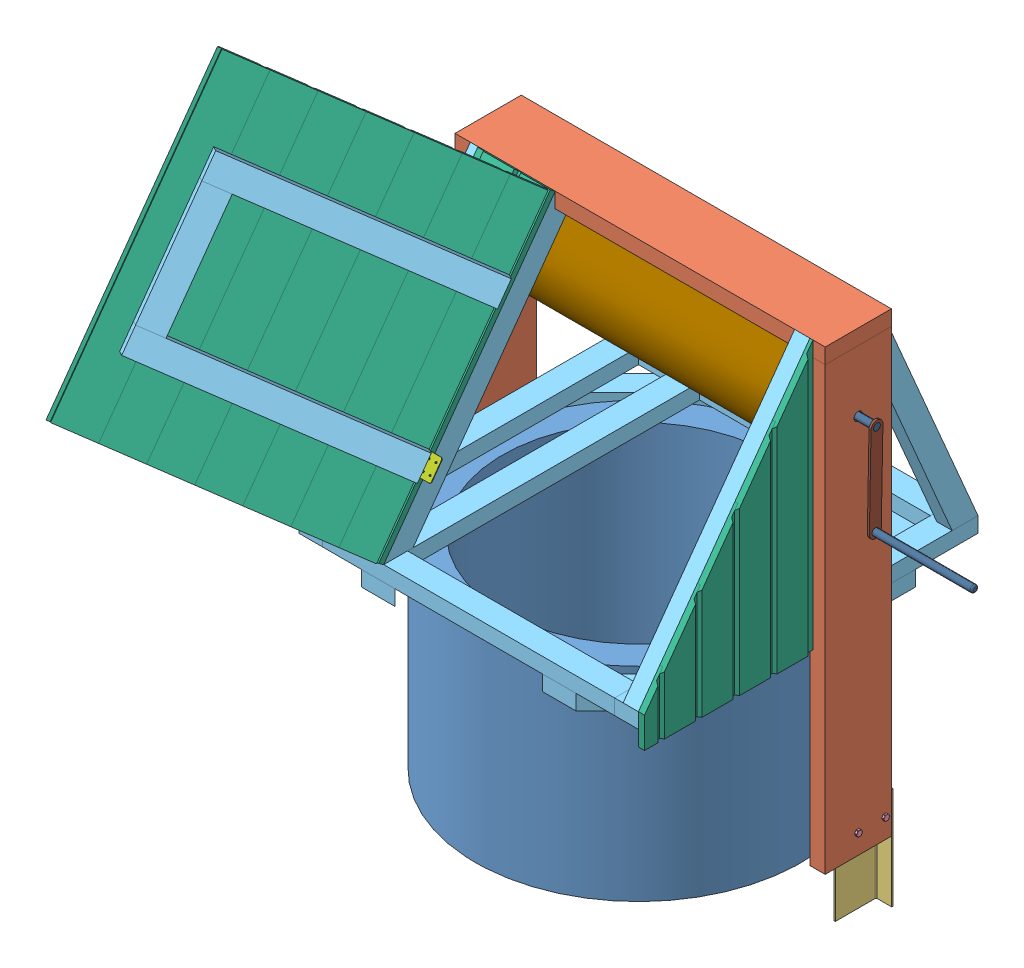
SolidWorks assembly well, configuration Default. Lengths in mm.
Overall size (1683.91 1861.34 1515.72).
55 component instances, 11 part files, 147 mates.
Components (placement in the parent):
- ring-1: ring [Default] at origin size (960 600 960)
- beam-45x195-1: beam-45x195 [Right] at (522.5 0 -102.5) x (0 0 -1) z (1 0 0) size (195 1300 45)
- beam-45x195-2: beam-45x195 [Left] at (-522.5 1300 -102.5) x (0 0 -1) z (-1 0 0) size (195 1300 45)
- beam-45x195-4: beam-45x195 [1090mm] at (545 1322.5 -102.5) x (0 0 1) z (0 -1 0) size (195 1090 45)
- side-mount-1: side-mount [Right] at (498 -180 -140) x (0 0 -1) z (1 0 0) size (124 300 50)
- side-mount-3: side-mount [Left] at (-498 120 -140) x (0 0 -1) z (-1 0 0) size (124 300 50)
- bolt-M10x60-1: bolt-M10x60 [Default] at (551.5 60 -180) x (0 1 0) z (0 0 1) size (16 66.5 17.98)
- bolt-M10x60-2: bolt-M10x60 [Default] at (551.5 60 -100) x (0 1 0) z (0 0 1) size (16 66.5 17.98)
- bolt-M10x60-4: bolt-M10x60 [Default] at (-551.5 60 -100) x (0 1 0) z (0 0 -1) size (16 66.5 17.98)
- bolt-M10x60-6: bolt-M10x60 [Default] at (-551.5 60 -180) x (0 1 0) z (0 0 -1) size (16 66.5 17.98)
- beam-45x70-1: beam-45x70 [1000mm] at (-465 622.5 -500) x (1 0 0) z (0 -1 0) size (70 1000 45)
- beam-45x70-2: beam-45x70 [1000mm] at (465 622.5 500) x (-1 0 0) z (0 -1 0) size (70 1000 45)
- beam-45x70-4: beam-45x70 [860mm] at (-430 622.5 465) x (0 0 1) z (0 1 0) size (70 860 45)
- beam-45x70-5: beam-45x70 [860mm] at (430 622.5 -465) x (0 0 -1) z (0 1 0) size (70 860 45)
- beam-45x70-7: beam-45x70 [860mm] at (-285 622.5 -430) x (1 0 0) z (0 -1 0) size (70 860 45)
- beam-45x70-8: beam-45x70 [Diagonal] at (-524.7487 577.5 241.906) x (-0.707107 0 0.707107) z (0 1 0) size (70 400 45)
- beam-45x70-9: beam-45x70 [Diagonal] at (524.7487 577.5 -241.906) x (0.707107 0 -0.707107) z (0 1 0) size (70 400 45)
- beam-45x70-11: beam-45x70 [Diagonal] at (241.906 577.5 524.7487) x (0.707107 0 0.707107) z (0 1 0) size (70 400 45)
- beam-45x70-13: beam-45x70 [Diagonal] at (-241.906 577.5 -524.7487) x (-0.707107 0 -0.707107) z (0 1 0) size (70 400 45)
- beam-45x70-15: beam-45x70 [Front diagonal] at (477.5 624.5226 471.6155) x (0 -0.585067 -0.810985) z (1 0 0) size (70 863.15 45)
- beam-45x70-17: beam-45x70 [Front diagonal] at (-477.5 624.5226 471.6155) x (0 -0.585067 -0.810985) z (1 0 0) size (70 863.15 45)
- beam-45x70-18: beam-45x70 [Front diagonal] at (-272.5 624.5226 471.6155) x (0 -0.585067 -0.810985) z (1 0 0) size (70 863.15 45)
- beam-45x70-20: beam-45x70 [Rear diagonal] at (-477.5 631.2128 -467.8299) x (0 -0.393919 0.919145) z (-1 0 0) size (70 761.58 45)
- beam-45x70-22: beam-45x70 [Rear diagonal] at (477.5 631.2128 -467.8299) x (0 -0.393919 0.919145) z (-1 0 0) size (70 761.58 45)
- weatherboard-18x120-1: weatherboard-18x120 [Right A] at (509 555 55) x (0 0 1) z (-1 0 0) size (120 790 18)
- weatherboard-18x120-3: weatherboard-18x120 [Right B] at (509 555 165.5) x (0 0 1) z (-1 0 0) size (120 636.83 18)
- weatherboard-18x120-6: weatherboard-18x120 [Right C] at (509 555 276) x (0 0 1) z (-1 0 0) size (120 483.66 18)
- weatherboard-18x120-8: weatherboard-18x120 [Right D] at (509 555 386.5) x (0 0 1) z (-1 0 0) size (120 330.5 18)
- weatherboard-18x120-10: weatherboard-18x120 [Right E] at (509 555 497) x (0 0 1) z (-1 0 0) size (63 177.33 18)
- weatherboard-18x120-12: weatherboard-18x120 [Front diagonal door mount] at (-300.5 1350.2656 2.2989) x (1 0 0) z (0 -0.585067 -0.810985) size (110.5 863.15 18)
- weatherboard-18x120-13: weatherboard-18x120 [Front diagonal normal] at (-411 1350.2656 2.2989) x (1 0 0) z (0 -0.585067 -0.810985) size (120 863.15 18)
- hinge-1: hinge [Default] at (-250 1170.76 146.5962) x (0 0.585067 0.810985) z (0 -0.810985 0.585067) size (70.41 34.65 60) (flexible)
  - hinge-side-1: hinge-side [A] at origin size (43 6 60)
  - hinge-side-2: hinge-side [B] at (2.1213 0.8787 0) x (-0.707107 -0.707107 0) z (0 0 -1) size (43 6 60)
  - hinge-pin-1: hinge-pin [Default] at (0 3 -30) x (1 0 0) z (0 -1 0) size (1.9 60 1.9)
- hinge-2: hinge [Default] at (-253 842.0577 380.0322) x (-1 0 0) z (0 0.810985 -0.585067) size (43 43 60) (flexible)
  - hinge-side-1: hinge-side [A] at origin size (43 6 60)
  - hinge-side-2: hinge-side [B] at (-3 3 0) x (0 1 0) z (0 0 -1) size (43 6 60)
  - hinge-pin-1: hinge-pin [Default] at (0 3 -30) x (0.057006 -0.998374 0) z (-0.998374 -0.057006 0) size (1.9 60 1.9)
- weatherboard-18x120-14: weatherboard-18x120 [Front diagonal door first] at (-272.3067 1378.5111 41.451) x (-0.707107 0.413705 0.573453) z (0.707107 0.413705 0.573453) size (96.3 863.15 18)
- beam-45x70-23: beam-45x70 [680mm] at (-705.1948 1471.3168 563.2096) x (0 0.810985 -0.585067) z (-0.707107 -0.413705 -0.573453) size (70 680 45)
- beam-45x70-24: beam-45x70 [680mm] at (-705.1948 1144.3697 799.0786) x (0 0.810985 -0.585067) z (-0.707107 -0.413705 -0.573453) size (70 680 45)
- beam-45x70-26: beam-45x70 [Door handle brace] at (-680.446 617.468 1148.6836) x (-0.707107 0.413705 0.573453) z (-0.707107 -0.413705 -0.573453) size (70 333.15 45)
- weatherboard-18x120-15: weatherboard-18x120 [Front diagonal normal] at (-350.442 1424.2255 104.8175) x (-0.707107 0.413705 0.573453) z (0.707107 0.413705 0.573453) size (120 863.15 18)
- weatherboard-18x120-16: weatherboard-18x120 [Front diagonal normal] at (-428.5773 1469.9399 168.1841) x (-0.707107 0.413705 0.573453) z (0.707107 0.413705 0.573453) size (120 863.15 18)
- weatherboard-18x120-17: weatherboard-18x120 [Front diagonal normal] at (-506.7126 1515.6544 231.5506) x (-0.707107 0.413705 0.573453) z (0.707107 0.413705 0.573453) size (120 863.15 18)
- weatherboard-18x120-18: weatherboard-18x120 [Front diagonal normal] at (-584.8479 1561.3688 294.9171) x (-0.707107 0.413705 0.573453) z (0.707107 0.413705 0.573453) size (120 863.15 18)
- weatherboard-18x120-19: weatherboard-18x120 [Front diagonal normal] at (-662.9832 1607.0832 358.2836) x (-0.707107 0.413705 0.573453) z (0.707107 0.413705 0.573453) size (120 863.15 18)
- weatherboard-18x120-20: weatherboard-18x120 [Front diagonal normal] at (-741.1185 1652.7976 421.6502) x (-0.707107 0.413705 0.573453) z (0.707107 0.413705 0.573453) size (120 863.15 18)
- roll-1: roll [Default] at (-450 1120 -102.5) x (0 -0.018379 -0.999831) z (1 0 0) size (250 250 900)
- bar-1: bar [Chamfered] at (-50 1120 -102.5) x (0 0.181671 0.983359) z (-1 0 0) size (20 20 500)
- handle-1: handle [Default] at (594 987.5224 -100.0648) x (0 -0.018379 -0.999831) z (0 -0.999831 0.018379) size (35 794 300)
  - handle-link-1: handle-link [Default] at origin size (35 6 300)
  - bar-1: bar [300mm] at (0 0 132.5) x (0.999562 0 -0.029607) z (0 1 0) size (20 20 300)
  - bar-2: bar [Chamfered] at (0 -494 -132.5) x (-0.665343 0 0.746538) z (0 1 0) size (20 20 500)
Mates (geometry in assembly coordinates):
- Coincident1: coincident aligned: plane of side-mount-1 through (498 120 -200) normal (0 0 1); plane of assembly through (0 0 -200) normal (0 0 1)
- Distance1: distance = 120 mm anti-aligned: plane of side-mount-1 through (498 120 -140) normal (0 1 0); plane of ring-1 through (0 0 0) normal (0 -1 0)
- Distance2: distance = 500 mm aligned: plane of side-mount-1 through (500 120 -140) normal (1 0 0); plane of assembly through (0 0 0) normal (1 0 0)
- Concentric1: concentric anti-aligned: cylinder of side-mount-1 through (495.999 60 -180) axis (1 0 0) radius 5.25; cylinder of ? through (-680.6384 60 -180) axis (-1 0 0) radius 5.25
- Concentric2: concentric anti-aligned: cylinder of side-mount-1 through (495.999 60 -100) axis (1 0 0) radius 5.25; cylinder of ? through (-680.6384 60 -100) axis (-1 0 0) radius 5.25
- Symmetric2: symmetric aligned: plane of side-mount-1 through (496 120 -140) normal (-1 0 0); plane of ? through (-496 120 -140) normal (1 0 0); plane of assembly through (0 0 0) normal (1 0 0)
- Concentric3: concentric anti-aligned: cylinder of side-mount-1 through (495.999 60 -180) axis (1 0 0) radius 5.25; cylinder of side-mount-3 through (-495.999 60 -180) axis (-1 0 0) radius 5.25
- Concentric4: concentric anti-aligned: cylinder of side-mount-1 through (495.999 60 -100) axis (1 0 0) radius 5.25; cylinder of side-mount-3 through (-495.999 60 -100) axis (-1 0 0) radius 5.25
- Coincident6: coincident aligned: plane of side-mount-1 through (498 120 -200) normal (0 0 1); plane of side-mount-3 through (-498 -180 -200) normal (0 0 1)
- Coincident7: coincident aligned: plane of side-mount-1 through (498 120 -140) normal (0 1 0); plane of side-mount-3 through (-498 120 -140) normal (0 1 0)
- Symmetric3: symmetric aligned: plane of side-mount-1 through (496 120 -140) normal (-1 0 0); plane of side-mount-3 through (-496 -180 -140) normal (1 0 0); plane of assembly through (0 0 0) normal (1 0 0)
- Coincident8: coincident anti-aligned: plane of side-mount-1 through (500 120 -140) normal (1 0 0); plane of beam-45x195-1 through (500 1300 -5) normal (-1 0 0)
- Coincident9: coincident anti-aligned: plane of side-mount-1 through (498 120 -200) normal (0 0 1); plane of beam-45x195-1 through (500 1300 -200) normal (0 0 -1)
- Coincident10: coincident aligned: plane of ring-1 through (0 0 0) normal (0 -1 0); plane of beam-45x195-1 through (522.5 0 -102.5) normal (0 -1 0)
- Coincident11: coincident anti-aligned: plane of beam-45x195-1 through (545 1300 -5) normal (1 0 0); plane of bolt-M10x60-1 through (545 60 -180) normal (-1 0 0)
- Concentric5: concentric aligned: cylinder of side-mount-1 through (495.999 60 -180) axis (1 0 0) radius 5.25; cylinder of bolt-M10x60-1 through (485 60 -180) axis (1 0 0) radius 5
- Coincident12: coincident anti-aligned: plane of beam-45x195-1 through (545 1300 -5) normal (1 0 0); plane of bolt-M10x60-2 through (545 60 -100) normal (-1 0 0)
- Concentric6: concentric aligned: cylinder of side-mount-1 through (495.999 60 -100) axis (1 0 0) radius 5.25; cylinder of bolt-M10x60-2 through (485 60 -100) axis (1 0 0) radius 5
- Coincident14: coincident anti-aligned: plane of side-mount-3 through (-500 -180 -140) normal (-1 0 0); plane of beam-45x195-2 through (-500 0 -5) normal (1 0 0)
- Coincident15: coincident anti-aligned: plane of side-mount-3 through (-498 -180 -200) normal (0 0 1); plane of beam-45x195-2 through (-500 0 -200) normal (0 0 -1)
- Coincident18: coincident aligned: plane of ring-1 through (0 0 0) normal (0 -1 0); plane of beam-45x195-2 through (-522.5 0 -102.5) normal (0 -1 0)
- Parallel1: parallel aligned: plane of beam-45x195-1 through (522.5 0 -102.5) normal (0 -1 0); plane of bolt-M10x60-2 through (545 52 -104.6188) normal (0 -1 0)
- Parallel2: parallel aligned: plane of beam-45x195-1 through (522.5 0 -102.5) normal (0 -1 0); plane of bolt-M10x60-1 through (545 52 -184.6188) normal (0 -1 0)
- Coincident21: coincident anti-aligned: plane of beam-45x195-2 through (-545 0 -5) normal (-1 0 0); plane of bolt-M10x60-4 through (-545 60 -100) normal (1 0 0)
- Concentric7: concentric aligned: cylinder of side-mount-3 through (-495.999 60 -100) axis (-1 0 0) radius 5.25; cylinder of bolt-M10x60-4 through (-485 60 -100) axis (-1 0 0) radius 5
- Parallel3: parallel aligned: plane of beam-45x195-2 through (-522.5 0 -102.5) normal (0 -1 0); plane of bolt-M10x60-4 through (-545 52 -95.3812) normal (0 -1 0)
- Coincident22: coincident anti-aligned: plane of beam-45x195-2 through (-545 0 -5) normal (-1 0 0); plane of bolt-M10x60-6 through (-545 60 -180) normal (1 0 0)
- Concentric8: concentric aligned: cylinder of side-mount-3 through (-495.999 60 -180) axis (-1 0 0) radius 5.25; cylinder of bolt-M10x60-6 through (-485 60 -180) axis (-1 0 0) radius 5
- Parallel4: parallel aligned: plane of beam-45x195-2 through (-522.5 0 -102.5) normal (0 -1 0); plane of bolt-M10x60-6 through (-545 52 -175.3812) normal (0 -1 0)
- Coincident23: coincident anti-aligned: plane of beam-45x195-2 through (-522.5 1300 -102.5) normal (0 1 0); plane of beam-45x195-4 through (-545 1300 -200) normal (0 -1 0)
- Coincident24: coincident aligned: plane of beam-45x195-2 through (-545 0 -5) normal (-1 0 0); plane of beam-45x195-4 through (-545 1322.5 -102.5) normal (-1 0 0)
- Coincident25: coincident aligned: plane of beam-45x195-2 through (-500 0 -5) normal (0 0 1); plane of beam-45x195-4 through (-545 1345 -5) normal (0 0 1)
- Coincident26: coincident anti-aligned: plane of ring-1 through (0 600 0) normal (0 1 0); plane of beam-45x70-1 through (-500 600 500) normal (0 -1 0)
- Coincident27: coincident anti-aligned: plane of beam-45x195-2 through (-500 0 -5) normal (1 0 0); plane of beam-45x70-1 through (-500 645 500) normal (-1 0 0)
- Symmetric4: symmetric aligned: plane of beam-45x70-1 through (-465 622.5 500) normal (0 0 1); plane of beam-45x70-1 through (-465 622.5 -500) normal (0 0 -1); plane of assembly through (0 0 0) normal (0 0 1)
- Coincident28: coincident anti-aligned: plane of ring-1 through (0 600 0) normal (0 1 0); plane of beam-45x70-2 through (500 600 -500) normal (0 -1 0)
- Coincident29: coincident anti-aligned: plane of beam-45x195-1 through (500 1300 -5) normal (-1 0 0); plane of beam-45x70-2 through (500 645 -500) normal (1 0 0)
- Symmetric5: symmetric aligned: plane of beam-45x70-2 through (465 622.5 -500) normal (0 0 -1); plane of beam-45x70-2 through (465 622.5 500) normal (0 0 1); plane of assembly through (0 0 0) normal (0 0 1)
- Coincident31: coincident aligned: plane of beam-45x70-1 through (-500 645 500) normal (0 1 0); plane of beam-45x70-4 through (430 645 430) normal (0 1 0)
- Coincident32: coincident anti-aligned: plane of beam-45x70-1 through (-430 645 500) normal (1 0 0); plane of beam-45x70-4 through (-430 622.5 465) normal (-1 0 0)
- Coincident33: coincident aligned: plane of beam-45x70-1 through (-465 622.5 500) normal (0 0 1); plane of beam-45x70-4 through (430 600 500) normal (0 0 1)
- Coincident34: coincident aligned: plane of beam-45x70-1 through (-500 645 500) normal (0 1 0); plane of beam-45x70-5 through (-430 645 -430) normal (0 1 0)
- Coincident35: coincident anti-aligned: plane of beam-45x70-2 through (430 645 -500) normal (-1 0 0); plane of beam-45x70-5 through (430 622.5 -465) normal (1 0 0)
- Coincident36: coincident aligned: plane of beam-45x70-2 through (465 622.5 -500) normal (0 0 -1); plane of beam-45x70-5 through (-430 600 -500) normal (0 0 -1)
- Coincident38: coincident aligned: plane of beam-45x70-1 through (-500 645 500) normal (0 1 0); plane of beam-45x70-7 through (-320 645 430) normal (0 1 0)
- Coincident39: coincident anti-aligned: plane of beam-45x70-4 through (430 600 430) normal (0 0 -1); plane of beam-45x70-7 through (-285 622.5 430) normal (0 0 1)
- Distance3: distance = 250 mm anti-aligned: plane of beam-45x70-7 through (-250 645 430) normal (1 0 0); plane of beam-45x70-1 through (-500 645 500) normal (-1 0 0)
- Coincident45: coincident aligned: plane of beam-45x70-4 through (430 600 500) normal (0 0 1); plane of beam-45x70-8 through (-524.7487 554.999 500) normal (0 0 1)
- Coincident46: coincident aligned: plane of beam-45x70-1 through (-500 645 500) normal (-1 0 0); plane of beam-45x70-8 through (-500 554.999 241.906) normal (-1 0 0)
- Coincident47: coincident anti-aligned: plane of beam-45x70-1 through (-500 600 500) normal (0 -1 0); plane of beam-45x70-8 through (-217.1573 600 500) normal (0 1 0)
- Coincident48: coincident aligned: plane of beam-45x70-5 through (-430 600 -500) normal (0 0 -1); plane of beam-45x70-9 through (524.7487 554.999 -500) normal (0 0 -1)
- Coincident49: coincident aligned: plane of beam-45x70-2 through (500 645 -500) normal (1 0 0); plane of beam-45x70-9 through (500 554.999 -241.906) normal (1 0 0)
- Coincident50: coincident anti-aligned: plane of beam-45x70-2 through (500 600 -500) normal (0 -1 0); plane of beam-45x70-9 through (217.1573 600 -500) normal (0 1 0)
- Coincident51: coincident aligned: plane of beam-45x70-2 through (500 645 -500) normal (1 0 0); plane of beam-45x70-11 through (500 554.999 524.7487) normal (1 0 0)
- Coincident52: coincident aligned: plane of beam-45x70-2 through (465 622.5 500) normal (0 0 1); plane of beam-45x70-11 through (241.906 554.999 500) normal (0 0 1)
- Coincident53: coincident anti-aligned: plane of beam-45x70-2 through (500 600 -500) normal (0 -1 0); plane of beam-45x70-11 through (500 600 217.1573) normal (0 1 0)
- Coincident54: coincident aligned: plane of beam-45x70-1 through (-500 645 500) normal (-1 0 0); plane of beam-45x70-13 through (-500 554.999 -524.7487) normal (-1 0 0)
- Coincident55: coincident aligned: plane of beam-45x70-1 through (-465 622.5 -500) normal (0 0 -1); plane of beam-45x70-13 through (-241.906 554.999 -500) normal (0 0 -1)
- Coincident56: coincident anti-aligned: plane of beam-45x70-1 through (-500 600 500) normal (0 -1 0); plane of beam-45x70-13 through (-500 600 -217.1573) normal (0 1 0)
- Coincident57: coincident aligned: line of beam-45x70-2 through (430 645 500) axis (1 0 0); line of beam-45x70-15 through (455 645 500) axis (1 0 0)
- Coincident58: coincident: line of beam-45x195-4 through (-545 1345 -5) axis (1 0 0); plane of beam-45x70-15 through (455 1455.9846 -85.0675) normal (0 0.585067 0.810985)
- Coincident59: coincident aligned: plane of beam-45x70-2 through (500 645 -500) normal (1 0 0); plane of beam-45x70-15 through (500 1455.9846 -85.0675) normal (1 0 0)
- Coincident63: coincident anti-aligned: line of beam-45x70-1 through (-430 645 500) axis (-1 0 0); line of beam-45x70-17 through (-500 645 500) axis (1 0 0)
- Coincident64: coincident aligned: line of beam-45x195-4 through (-545 1345 -5) axis (1 0 0); line of beam-45x70-17 through (-500 1345 -5) axis (1 0 0)
- Coincident65: coincident aligned: plane of beam-45x70-1 through (-500 645 500) normal (-1 0 0); plane of beam-45x70-17 through (-500 1455.9846 -85.0675) normal (-1 0 0)
- Coincident66: coincident anti-aligned: line of beam-45x70-1 through (-430 645 500) axis (-1 0 0); line of beam-45x70-18 through (-295 645 500) axis (1 0 0)
- Coincident67: coincident aligned: line of beam-45x195-4 through (-545 1345 -5) axis (1 0 0); line of beam-45x70-18 through (-295 1345 -5) axis (1 0 0)
- Coincident71: coincident aligned: plane of beam-45x70-7 through (-250 645 430) normal (1 0 0); plane of beam-45x70-18 through (-250 1455.9846 -85.0675) normal (1 0 0)
- Coincident73: coincident: line of beam-45x195-4 through (-545 1345 -200) axis (1 0 0); plane of beam-45x70-20 through (-455 1564.145 -106.0807) normal (0 0.393919 -0.919145)
- Coincident74: coincident aligned: plane of beam-45x70-1 through (-500 645 500) normal (-1 0 0); plane of beam-45x70-20 through (-500 1564.145 -106.0807) normal (-1 0 0)
- Coincident75: coincident aligned: line of beam-45x70-1 through (-430 645 -500) axis (-1 0 0); line of beam-45x70-20 through (-455 645 -500) axis (-1 0 0)
- Coincident79: coincident anti-aligned: line of beam-45x70-2 through (430 645 -500) axis (1 0 0); line of beam-45x70-22 through (500 645 -500) axis (-1 0 0)
- Coincident80: coincident anti-aligned: line of beam-45x195-4 through (-545 1345 -200) axis (1 0 0); line of beam-45x70-22 through (500 1345 -200) axis (-1 0 0)
- Coincident81: coincident aligned: plane of beam-45x70-2 through (500 645 -500) normal (1 0 0); plane of beam-45x70-22 through (500 1564.145 -106.0807) normal (1 0 0)
- Coincident82: coincident anti-aligned: plane of beam-45x70-2 through (500 645 -500) normal (1 0 0); plane of weatherboard-18x120-1 through (500 1355 55) normal (-1 0 0)
- Coincident83: coincident anti-aligned: plane of beam-45x195-1 through (500 1300 -5) normal (0 0 1); plane of weatherboard-18x120-1 through (509 1355 -5) normal (0 0 -1)
- Distance4: distance = 45 mm aligned: plane of weatherboard-18x120-1 through (509 555 55) normal (0 -1 0); plane of beam-45x70-2 through (500 600 -500) normal (0 -1 0)
- Coincident88: coincident anti-aligned: plane of weatherboard-18x120-1 through (509 1355 105.5) normal (0 0 1); plane of weatherboard-18x120-3 through (509 1355 105.5) normal (0 0 -1)
- Coincident89: coincident aligned: plane of weatherboard-18x120-1 through (509 555 55) normal (0 -1 0); plane of weatherboard-18x120-3 through (509 555 165.5) normal (0 -1 0)
- Coincident90: coincident anti-aligned: plane of weatherboard-18x120-1 through (509 1355 55) normal (-1 0 0); plane of weatherboard-18x120-3 through (509 1355 165.5) normal (1 0 0)
- Coincident91: coincident anti-aligned: plane of weatherboard-18x120-3 through (509 1500 216) normal (0 0 1); plane of ? through (362.1952 1500 216) normal (0 0 -1)
- Coincident92: coincident aligned: plane of weatherboard-18x120-1 through (509 500 55) normal (0 -1 0); plane of ? through (362.1952 500 276) normal (0 -1 0)
- Coincident94: coincident anti-aligned: plane of weatherboard-18x120-3 through (509 1500 165.5) normal (-1 0 0); plane of ? through (509 1500 276) normal (1 0 0)
- Coincident95: coincident anti-aligned: plane of weatherboard-18x120-3 through (509 1355 216) normal (0 0 1); plane of weatherboard-18x120-6 through (509 1355 216) normal (0 0 -1)
- Coincident96: coincident aligned: plane of weatherboard-18x120-3 through (509 555 165.5) normal (0 -1 0); plane of weatherboard-18x120-6 through (509 555 276) normal (0 -1 0)
- Coincident98: coincident anti-aligned: plane of weatherboard-18x120-3 through (509 1355 165.5) normal (-1 0 0); plane of weatherboard-18x120-6 through (509 1355 276) normal (1 0 0)
- Coincident99: coincident anti-aligned: plane of weatherboard-18x120-6 through (509 1355 326.5) normal (0 0 1); plane of weatherboard-18x120-8 through (509 1355 326.5) normal (0 0 -1)
- Coincident100: coincident aligned: plane of weatherboard-18x120-6 through (509 555 276) normal (0 -1 0); plane of weatherboard-18x120-8 through (509 555 386.5) normal (0 -1 0)
- Coincident101: coincident anti-aligned: plane of weatherboard-18x120-6 through (509 1355 276) normal (-1 0 0); plane of weatherboard-18x120-8 through (509 1355 386.5) normal (1 0 0)
- Coincident102: coincident anti-aligned: plane of weatherboard-18x120-8 through (509 1355 437) normal (0 0 1); plane of weatherboard-18x120-10 through (509 1355 437) normal (0 0 -1)
- Coincident103: coincident aligned: plane of weatherboard-18x120-8 through (509 555 386.5) normal (0 -1 0); plane of weatherboard-18x120-10 through (509 555 497) normal (0 -1 0)
- Coincident104: coincident anti-aligned: plane of weatherboard-18x120-8 through (509 1355 386.5) normal (-1 0 0); plane of weatherboard-18x120-10 through (509 1355 497) normal (1 0 0)
- Coincident105: coincident anti-aligned: plane of beam-45x70-17 through (-500 1455.9846 -85.0675) normal (0 0.585067 0.810985); plane of weatherboard-18x120-12 through (-300.5 534.0154 580.0675) normal (0 -0.585067 -0.810985)
- Coincident106: coincident aligned: line of beam-45x195-4 through (-545 1345 -5) axis (1 0 0); line of weatherboard-18x120-12 through (-360.5 1345 -5) axis (1 0 0)
- Coincident107: coincident aligned: plane of beam-45x70-18 through (-250 1455.9846 -85.0675) normal (1 0 0); plane of weatherboard-18x120-12 through (-250 539.281 587.3663) normal (1 0 0)
- Coincident108: coincident anti-aligned: plane of weatherboard-18x120-12 through (-300.5 539.281 587.3663) normal (0 0.585067 0.810985); plane of weatherboard-18x120-13 through (-411 539.281 587.3663) normal (0 -0.585067 -0.810985)
- Coincident109: coincident anti-aligned: plane of weatherboard-18x120-12 through (-360.5 539.281 587.3663) normal (-1 0 0); plane of weatherboard-18x120-13 through (-360.5 539.281 587.3663) normal (1 0 0)
- Coincident110: coincident aligned: plane of weatherboard-18x120-12 through (-300.5 1350.2656 2.2989) normal (0 0.810985 -0.585067); plane of weatherboard-18x120-13 through (-411 1350.2656 2.2989) normal (0 0.810985 -0.585067)
- Distance7: distance = 200 mm aligned: plane of hinge-1/hinge-side-1 through (-252 1171.6868 96.6048) normal (0 0.810985 -0.585067); plane of weatherboard-18x120-12 through (-300.5 1350.2656 2.2989) normal (0 0.810985 -0.585067)
- Coincident114: coincident aligned: plane of hinge-1/hinge-side-1 through (-250 1170.76 146.5962) normal (1 0 0); plane of hinge-2/hinge-side-2 through (-250 843.8129 382.4652) normal (1 0 0)
- Coincident116: coincident aligned: plane of hinge-1/hinge-side-1 through (-252 1171.6868 96.6048) normal (0 -0.585067 -0.810985); plane of hinge-2/hinge-side-2 through (-252 844.7397 332.4737) normal (0 -0.585067 -0.810985)
- Distance8: distance = 200 mm aligned: plane of hinge-2/hinge-side-2 through (-252 796.0806 367.5778) normal (0 -0.810985 0.585067); plane of weatherboard-18x120-12 through (-300.5 644.9994 499.9992) normal (0 -0.810985 0.585067)
- Coincident122: coincident aligned: plane of weatherboard-18x120-12 through (-250 539.281 587.3663) normal (1 0 0); plane of hinge-1/hinge-side-1 through (-250 1170.76 146.5962) normal (1 0 0)
- Coincident123: coincident anti-aligned: plane of weatherboard-18x120-12 through (-300.5 544.5466 594.6652) normal (0 0.585067 0.810985); plane of hinge-1/hinge-side-1
- Coincident126: coincident anti-aligned: plane of hinge-1/hinge-side-2 through (-250.8787 1172.0011 148.3166) normal (0.707107 0.413705 0.573453); plane of weatherboard-18x120-14 through (-278.6707 563.8031 621.3574) normal (-0.707107 -0.413705 -0.573453)
- Coincident131: coincident anti-aligned: plane of weatherboard-18x120-14 through (-265.9428 571.2498 631.6796) normal (0.707107 0.413705 0.573453); plane of beam-45x70-23 through (-240.2721 1152.3044 180.8364) normal (-0.707107 -0.413705 -0.573453)
- Coincident133: coincident aligned: plane of weatherboard-18x120-14 through (-240.2714 1367.2158 25.7941) normal (0.707107 -0.413705 -0.573453); plane of beam-45x70-23 through (-224.3622 1189.9972 173.2617) normal (0.707107 -0.413705 -0.573453)
- Width1: width anti-aligned: plane of beam-45x70-23 through (-208.4523 1227.6901 165.6871) normal (0 0.810985 -0.585067); plane of beam-45x70-23 through (-208.4523 1170.9212 206.6418) normal (0 -0.810985 0.585067); plane of hinge-1/hinge-side-2 through (-280.5772 1163.3923 187.6598) normal (0 -0.810985 0.585067); plane of hinge-1/hinge-side-2 through (-280.5772 1212.0514 152.5557) normal (0 0.810985 -0.585067)
- Coincident134: coincident anti-aligned: plane of weatherboard-18x120-14 through (-265.9428 571.2498 631.6796) normal (0.707107 0.413705 0.573453); plane of beam-45x70-24 through (-240.2721 825.3573 416.7054) normal (-0.707107 -0.413705 -0.573453)
- Width2: width anti-aligned: plane of beam-45x70-24 through (-208.4523 900.743 401.556) normal (0 0.810985 -0.585067); plane of beam-45x70-24 through (-208.4523 843.9741 442.5108) normal (0 -0.810985 0.585067); plane of hinge-2/hinge-side-1 through (-213 867.5574 364.1021) normal (0 0.810985 -0.585067); plane of hinge-2/hinge-side-1 through (-213 818.8983 399.2062) normal (0 -0.810985 0.585067)
- Coincident138: coincident anti-aligned: plane of beam-45x70-23 through (-208.4523 1170.9212 206.6418) normal (0 -0.810985 0.585067); plane of beam-45x70-26 through (-680.446 1428.4526 563.6161) normal (0 0.810985 -0.585067)
- Coincident140: coincident aligned: plane of beam-45x70-23 through (-705.1948 1471.3168 563.2096) normal (-0.707107 0.413705 0.573453); plane of beam-45x70-26 through (-689.2849 1452.2407 596.5896) normal (-0.707107 0.413705 0.573453)
- Coincident141: coincident aligned: plane of beam-45x70-23 through (-240.2721 1152.3044 180.8364) normal (-0.707107 -0.413705 -0.573453); plane of beam-45x70-26 through (-671.6072 1404.6646 530.6426) normal (-0.707107 -0.413705 -0.573453)
- Coincident142: coincident aligned: plane of weatherboard-18x120-12 through (-300.5 1350.2656 2.2989) normal (0 0.810985 -0.585067); plane of weatherboard-18x120-14 through (-272.3067 1378.5111 41.451) normal (0 0.810985 -0.585067)
- Coincident143: coincident aligned: plane of beam-45x70-23 through (-224.3622 1189.9972 173.2617) normal (0.707107 -0.413705 -0.573453); plane of beam-45x70-24 through (-224.3622 863.0502 409.1307) normal (0.707107 -0.413705 -0.573453)
- Coincident145: coincident anti-aligned: plane of hinge-1/hinge-side-2; plane of weatherboard-18x120-14 through (-240.2714 1367.2158 25.7941) normal (0.707107 -0.413705 -0.573453)
- Coincident146: coincident anti-aligned: plane of beam-45x70-23 through (-240.2721 1152.3044 180.8364) normal (-0.707107 -0.413705 -0.573453); plane of weatherboard-18x120-15 through (-344.0781 616.9642 695.0461) normal (0.707107 0.413705 0.573453)
- Coincident147: coincident anti-aligned: plane of weatherboard-18x120-14 through (-272.3067 567.5265 626.5185) normal (0.707107 0.413705 0.573453); plane of weatherboard-18x120-15 through (-350.442 613.2409 689.885) normal (-0.707107 -0.413705 -0.573453)
- Coincident148: coincident anti-aligned: plane of weatherboard-18x120-14 through (-308.0156 588.4186 655.4778) normal (-0.707107 0.413705 0.573453); plane of weatherboard-18x120-15 through (-308.0156 588.4186 655.4778) normal (0.707107 -0.413705 -0.573453)
- Coincident149: coincident aligned: plane of weatherboard-18x120-14 through (-272.3067 1378.5111 41.451) normal (0 0.810985 -0.585067); plane of weatherboard-18x120-15 through (-350.442 1424.2255 104.8175) normal (0 0.810985 -0.585067)
- Coincident150: coincident anti-aligned: plane of beam-45x70-23 through (-240.2721 1152.3044 180.8364) normal (-0.707107 -0.413705 -0.573453); plane of weatherboard-18x120-16 through (-422.2134 662.6787 758.4126) normal (0.707107 0.413705 0.573453)
- Coincident151: coincident anti-aligned: plane of weatherboard-18x120-15 through (-350.442 613.2409 689.885) normal (0.707107 0.413705 0.573453); plane of weatherboard-18x120-16 through (-428.5773 658.9553 753.2515) normal (-0.707107 -0.413705 -0.573453)
- Coincident152: coincident anti-aligned: plane of weatherboard-18x120-15 through (-386.1509 634.133 718.8444) normal (-0.707107 0.413705 0.573453); plane of weatherboard-18x120-16 through (-386.1509 634.133 718.8444) normal (0.707107 -0.413705 -0.573453)
- Coincident153: coincident aligned: plane of weatherboard-18x120-15 through (-350.442 1424.2255 104.8175) normal (0 0.810985 -0.585067); plane of weatherboard-18x120-16 through (-428.5773 1469.9399 168.1841) normal (0 0.810985 -0.585067)
- Coincident154: coincident anti-aligned: plane of beam-45x70-23 through (-240.2721 1152.3044 180.8364) normal (-0.707107 -0.413705 -0.573453); plane of weatherboard-18x120-17 through (-500.3487 708.3931 821.7791) normal (0.707107 0.413705 0.573453)
- Coincident155: coincident anti-aligned: plane of weatherboard-18x120-16 through (-428.5773 658.9553 753.2515) normal (0.707107 0.413705 0.573453); plane of weatherboard-18x120-17 through (-506.7126 704.6697 816.6181) normal (-0.707107 -0.413705 -0.573453)
- Coincident156: coincident anti-aligned: plane of weatherboard-18x120-16 through (-464.2862 679.8474 782.2109) normal (-0.707107 0.413705 0.573453); plane of weatherboard-18x120-17 through (-464.2862 679.8474 782.2109) normal (0.707107 -0.413705 -0.573453)
- Coincident157: coincident aligned: plane of weatherboard-18x120-16 through (-428.5773 1469.9399 168.1841) normal (0 0.810985 -0.585067); plane of weatherboard-18x120-17 through (-506.7126 1515.6544 231.5506) normal (0 0.810985 -0.585067)
- Coincident158: coincident anti-aligned: plane of beam-45x70-23 through (-240.2721 1152.3044 180.8364) normal (-0.707107 -0.413705 -0.573453); plane of weatherboard-18x120-18 through (-578.484 754.1075 885.1457) normal (0.707107 0.413705 0.573453)
- Coincident159: coincident anti-aligned: plane of weatherboard-18x120-17 through (-506.7126 704.6697 816.6181) normal (0.707107 0.413705 0.573453); plane of weatherboard-18x120-18 through (-584.8479 750.3842 879.9846) normal (-0.707107 -0.413705 -0.573453)
- Coincident160: coincident anti-aligned: plane of weatherboard-18x120-17 through (-542.4215 725.5618 845.5774) normal (-0.707107 0.413705 0.573453); plane of weatherboard-18x120-18 through (-542.4215 725.5618 845.5774) normal (0.707107 -0.413705 -0.573453)
- Coincident161: coincident aligned: plane of weatherboard-18x120-17 through (-506.7126 1515.6544 231.5506) normal (0 0.810985 -0.585067); plane of weatherboard-18x120-18 through (-584.8479 1561.3688 294.9171) normal (0 0.810985 -0.585067)
- Coincident162: coincident anti-aligned: plane of beam-45x70-23 through (-240.2721 1152.3044 180.8364) normal (-0.707107 -0.413705 -0.573453); plane of weatherboard-18x120-19 through (-656.6193 799.8219 948.5122) normal (0.707107 0.413705 0.573453)
- Coincident163: coincident anti-aligned: plane of weatherboard-18x120-18 through (-584.8479 750.3842 879.9846) normal (0.707107 0.413705 0.573453); plane of weatherboard-18x120-19 through (-662.9832 796.0986 943.3511) normal (-0.707107 -0.413705 -0.573453)
- Coincident164: coincident anti-aligned: plane of weatherboard-18x120-18 through (-620.5568 771.2763 908.9439) normal (-0.707107 0.413705 0.573453); plane of weatherboard-18x120-19 through (-620.5568 771.2763 908.9439) normal (0.707107 -0.413705 -0.573453)
- Coincident165: coincident aligned: plane of weatherboard-18x120-18 through (-584.8479 1561.3688 294.9171) normal (0 0.810985 -0.585067); plane of weatherboard-18x120-19 through (-662.9832 1607.0832 358.2836) normal (0 0.810985 -0.585067)
- Coincident166: coincident anti-aligned: plane of beam-45x70-23 through (-240.2721 1152.3044 180.8364) normal (-0.707107 -0.413705 -0.573453); plane of weatherboard-18x120-20 through (-734.7546 845.5363 1011.8787) normal (0.707107 0.413705 0.573453)
- Coincident167: coincident anti-aligned: plane of weatherboard-18x120-19 through (-662.9832 796.0986 943.3511) normal (0.707107 0.413705 0.573453); plane of weatherboard-18x120-20 through (-741.1185 841.813 1006.7176) normal (-0.707107 -0.413705 -0.573453)
- Coincident168: coincident anti-aligned: plane of weatherboard-18x120-19 through (-698.6921 816.9907 972.3105) normal (-0.707107 0.413705 0.573453); plane of weatherboard-18x120-20 through (-698.6921 816.9907 972.3105) normal (0.707107 -0.413705 -0.573453)
- Coincident169: coincident aligned: plane of weatherboard-18x120-19 through (-662.9832 1607.0832 358.2836) normal (0 0.810985 -0.585067); plane of weatherboard-18x120-20 through (-741.1185 1652.7976 421.6502) normal (0 0.810985 -0.585067)
- Width3: width anti-aligned: plane of beam-45x195-2 through (-500 0 -5) normal (1 0 0); plane of beam-45x195-1 through (500 1300 -5) normal (-1 0 0); plane of roll-1 through (-450 1120 -102.5) normal (-1 0 0); plane of roll-1 through (450 1120 -102.5) normal (1 0 0)
- Concentric9: concentric aligned: cylinder of beam-45x195-2 through (-499.999 1120 -102.5) axis (-1 0 0) radius 12.5; cylinder of roll-1 through (-50 1120 -102.5) axis (-1 0 0) radius 10
- Concentric10: concentric anti-aligned: cylinder of roll-1 through (-50 1120 -102.5) axis (-1 0 0) radius 10; cylinder of bar-1 through (-550 1120 -102.5) axis (1 0 0) radius 10
- Coincident170: coincident anti-aligned: plane of roll-1 through (-50 1120 -102.5) normal (-1 0 0); plane of bar-1 through (-50 1120 -102.5) normal (1 0 0)
- Concentric11: concentric anti-aligned: cylinder of roll-1 through (100 1120 -102.5) axis (1 0 0) radius 10; cylinder of handle-1/bar-2 through (600 1120 -102.5) axis (-1 0 0) radius 10
- Coincident171: coincident anti-aligned: plane of roll-1 through (100 1120 -102.5) normal (1 0 0); plane of handle-1/bar-2 through (100 1120 -102.5) normal (-1 0 0)
- Parallel6: parallel anti-aligned: plane of roll-1; plane of handle-1/handle-link-1 through (594 987.5224 -100.0648) normal (0 -0.999831 0.018379)
